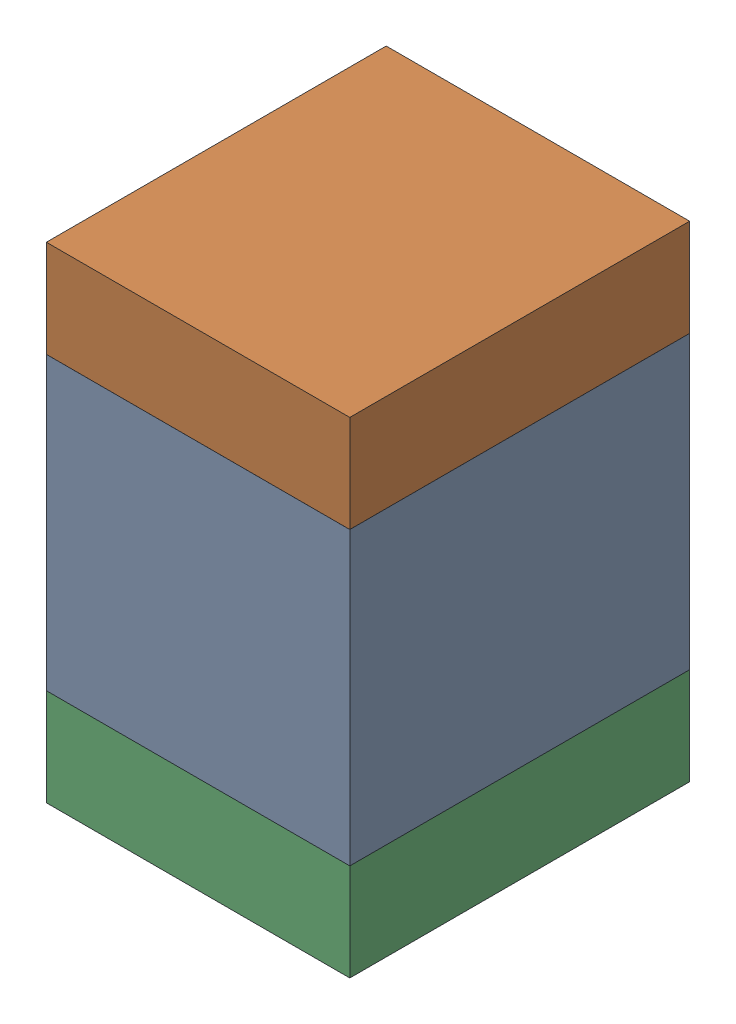
SolidWorks assembly C36, configuration ﾃﾞﾌｫﾙﾄ. Lengths in mm.
Overall size (1.25 2 1.4).
6 component instances, 2 part files, 0 mates.
Components (placement in the parent):
- 689259472-1: 689259472 [ﾃﾞﾌｫﾙﾄ] at (71.25 13.75 0) size (1.25 1.2 1.4)
  - Extruded_9-1: Extruded_9 [ﾃﾞﾌｫﾙﾄ] at origin size (1.25 1.2 1.4)
- 689259336-1: 689259336 [ﾃﾞﾌｫﾙﾄ] at (71.25 14.5501 0) size (1.25 0.4 1.4)
  - Extruded_8-1: Extruded_8 [ﾃﾞﾌｫﾙﾄ] at origin size (1.25 0.4 1.4)
- 689259336-2: 689259336 [ﾃﾞﾌｫﾙﾄ] at (71.25 12.9501 0) size (1.25 0.4 1.4)
  - Extruded_8-1: Extruded_8 [ﾃﾞﾌｫﾙﾄ] at origin size (1.25 0.4 1.4)
